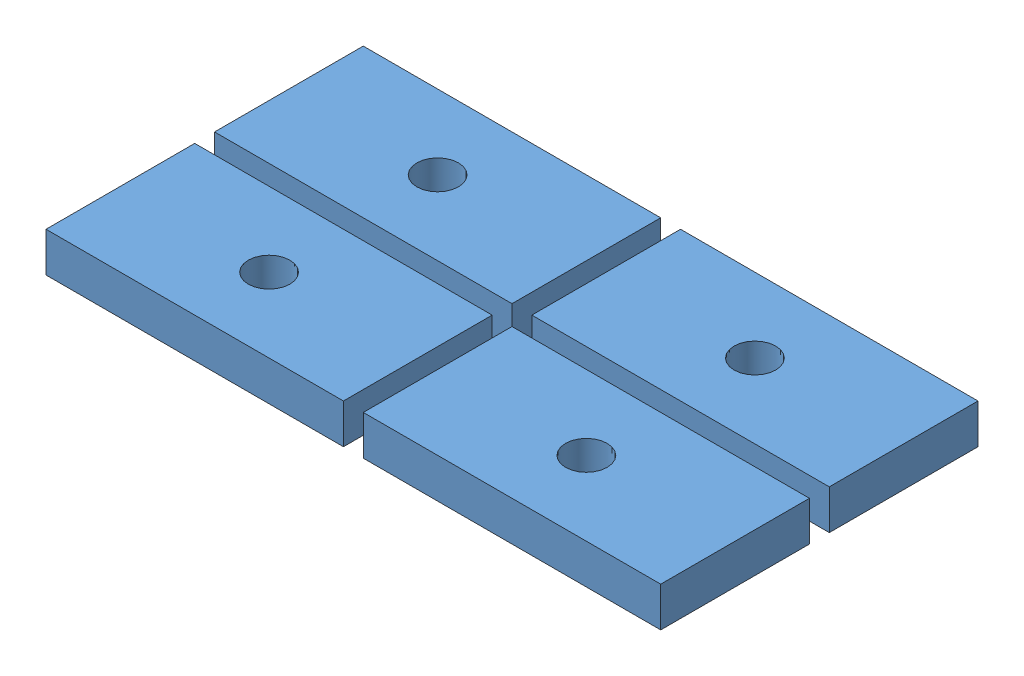
SolidWorks assembly Baugruppe3, configuration Standard. Lengths in mm.
Overall size (62 4 32).
4 component instances, 1 part files, 0 mates.
Components (placement in the parent):
- Lager-Montagehilfe-1: Lager-Montagehilfe [Standard] at (11.3705 13.9729 0) size (30 4 15)
- Lager-Montagehilfe-2: Lager-Montagehilfe [Standard] at (11.3705 13.9729 -17) size (30 4 15)
- Lager-Montagehilfe-3: Lager-Montagehilfe [Standard] at (43.3705 13.9729 0) size (30 4 15)
- Lager-Montagehilfe-4: Lager-Montagehilfe [Standard] at (43.3705 13.9729 -17) size (30 4 15)
